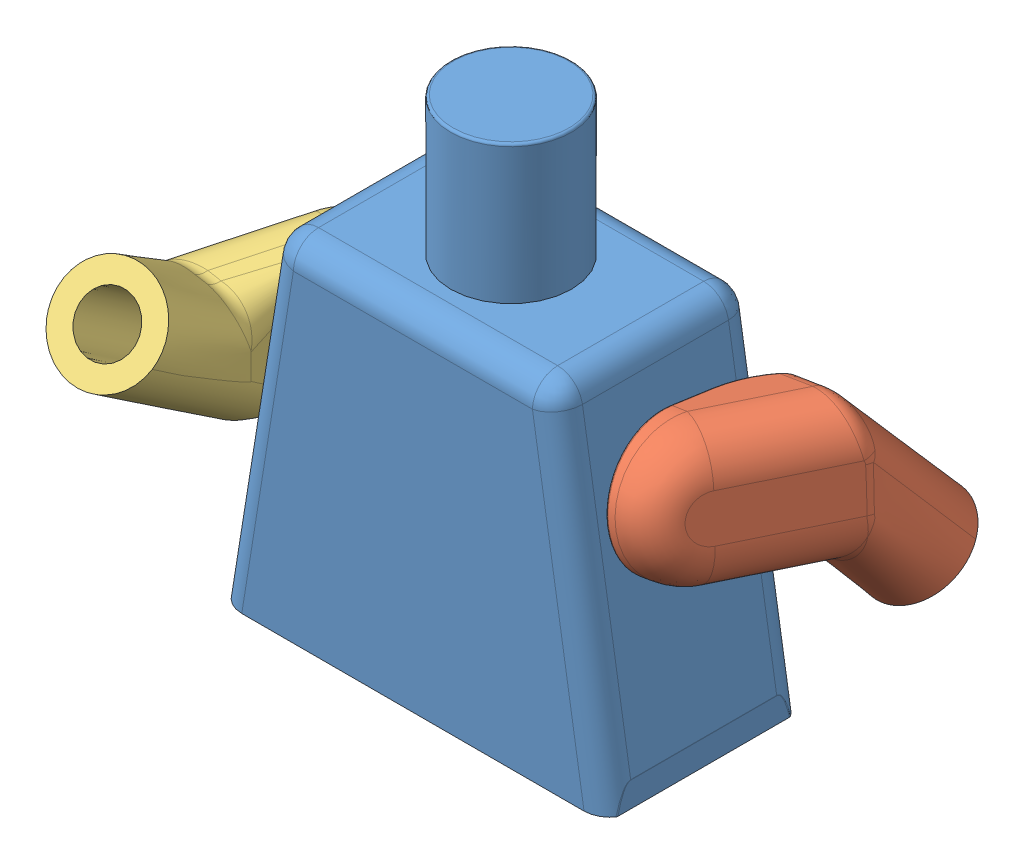
SolidWorks assembly Practice Model - Lego in Progress, configuration Default. Lengths in mm.
Overall size (22.38 19.3 18.93).
3 component instances, 3 part files, 4 mates.
Components (placement in the parent):
- Practice Model - Lego Torso in progress-1: Practice Model - Lego Torso in progress [Default] at origin size (15.31 19.3 7.8)
- Practice Model - Lego arm in progress-1: Practice Model - Lego arm in progress [Default] at (8.3967 8.9849 -1.9344) x (0.987417 0.158141 0) z (0.156875 -0.979512 0.126281) size (7.07 11.6 7.6)
- MirrorPractice Model - Lego arm in progress1-4: MirrorPractice Model - Lego arm in progress1 [Default] at (-8.4065 8.9234 1.9254) x (-0.987417 0.158141 0) z (-0.156149 -0.974979 -0.158221) size (7.07 11.6 7.6)
Mates (geometry in assembly coordinates):
- Concentric1: concentric aligned: cylinder of Practice Model - Lego Torso in progress-1 through (-8.6918 6.4975 0) axis (0.987417 0.158141 0) radius 1.9; cylinder of Practice Model - Lego arm in progress-1 through (6.3829 8.9118 0) axis (0.987417 0.158141 0) radius 1.85
- Coincident1: coincident anti-aligned: plane of Practice Model - Lego Torso in progress-1 through (7.65 1 3.9) normal (0.987417 0.158141 0); plane of Practice Model - Lego arm in progress-1 through (6.4218 8.6686 -1.9344) normal (-0.987417 -0.158141 0)
- Concentric2: concentric aligned: cylinder of Practice Model - Lego Torso in progress-1 through (8.6918 6.4975 0) axis (-0.987417 0.158141 0) radius 1.9; cylinder of MirrorPractice Model - Lego arm in progress1-4 through (-6.3829 8.9118 0) axis (-0.987417 0.158141 0) radius 1.85
- Coincident2: coincident anti-aligned: plane of Practice Model - Lego Torso in progress-1 through (-7.65 1 3.9) normal (-0.987417 0.158141 0); plane of MirrorPractice Model - Lego arm in progress1-4 through (-6.4317 8.6071 1.9254) normal (0.987417 -0.158141 0)
